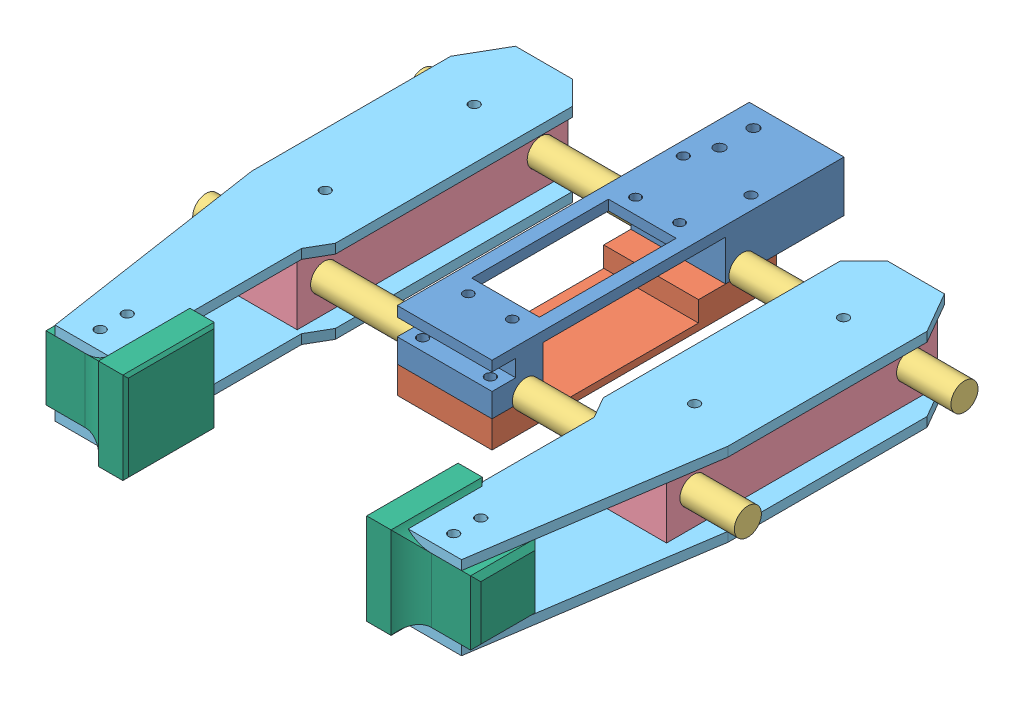
SolidWorks assembly gripper_assembly, configuration Default. Lengths in mm.
Overall size (160 27 162.34).
12 component instances, 6 part files, 24 mates.
Components (placement in the parent):
- gripper_main-1: gripper_main [Default] at (-49.2685 12.2427 53.1978) size (28 15 104)
- top-1: top [Default] at origin size (28 8 84)
- 8mm rod-1: 8mm rod [Default] at (-115.6958 13.7427 -20.8022) x (0 0.664083 0.747659) z (1 0 0) size (8 8 160)
- 8mm rod-2: 8mm rod [Default] at (-115.6958 13.7427 43.1978) x (0 -0.430781 0.902456) z (1 0 0) size (8 8 160)
- cube_part-1: cube_part [Default] at (9.2864 23.2427 51.1978) x (1 0 0) z (0 1 0) size (19 80 19)
- sideplate-1: sideplate [Default] at (14.5778 25.6427 47.7118) x (-1 0 0) z (0 0 1) size (30.8 2.8 139.34)
- sideplate-2: sideplate [Default] at (14.5778 3.8427 47.7118) x (-1 0 0) z (0 0 1) size (30.8 2.8 139.34)
- holdcube-1: holdcube [Default] at (28.2361 23.2427 107.5352) x (-1 0 0) z (0 0 1) size (29 27 27)
- cube_part-2: cube_part [Default] at (-99.8318 4.2427 -28.8022) x (1 0 0) z (0 -1 0) size (19 80 19)
- sideplate-3: sideplate [Default] at (-86.5416 1.8427 47.7118) size (30.8 2.8 139.34)
- sideplate-4: sideplate [Default] at (-86.5416 23.6427 47.7118) size (30.8 2.8 139.34)
- holdcube-2: holdcube [Default] at (-100.1999 4.2427 107.5352) size (29 27 27)
Mates (geometry in assembly coordinates):
- Concentric1: concentric anti-aligned: cylinder of gripper_main-1 through (-21.2685 13.7427 -20.8022) axis (-1 0 0) radius 4; circle of 8mm rod-1
- Coincident2: coincident anti-aligned: cylinder of gripper_main-1 through (-21.2685 13.7427 43.1978) axis (-1 0 0) radius 4; circle of 8mm rod-2
- Concentric2: concentric aligned: circle of 8mm rod-1; circle of cube_part-1
- Concentric3: concentric aligned: circle of 8mm rod-2; circle of cube_part-1
- Coincident6: coincident anti-aligned: plane of cube_part-1 through (9.2864 23.2427 -28.8022) normal (0 1 0); plane of sideplate-1 through (12.9839 23.2427 53.9262) normal (0 -1 0)
- Parallel1: parallel anti-aligned: line of cube_part-1 through (28.2864 4.2427 -28.8022) axis (-1 0 0); line of sideplate-1 through (10.5772 23.2427 -31.8022) axis (1 0 0)
- Coincident13: coincident anti-aligned: plane of cube_part-1 through (9.2864 4.2427 -28.8022) normal (0 -1 0); plane of sideplate-2 through (12.9839 4.2427 53.9262) normal (0 1 0)
- Concentric4: concentric aligned: circle of sideplate-1; circle of sideplate-2
- Parallel3: parallel aligned: line of sideplate-1 through (10.5772 23.2427 -31.8022) axis (1 0 0); line of sideplate-2 through (10.5772 1.4427 -31.8022) axis (1 0 0)
- Coincident17: coincident anti-aligned: plane of sideplate-2 through (12.9839 4.2427 53.9262) normal (0 1 0); plane of holdcube-1 through (28.2361 4.2427 107.5352) normal (0 -1 0)
- Concentric5: concentric aligned: cylinder of sideplate-1 through (16.2361 26.0427 94.0352) axis (0 -1 0) radius 1.5; circle of holdcube-1
- Concentric6: concentric aligned: circle of sideplate-1; circle of holdcube-1
- Coincident21: coincident aligned: plane of 8mm rod-1 through (44.3042 13.7427 -20.8022) normal (1 0 0); plane of 8mm rod-2 through (44.3042 13.7427 43.1978) normal (1 0 0)
- Concentric7: concentric aligned: circle of 8mm rod-1; cylinder of cube_part-2 through (-99.8318 13.7427 -20.8022) axis (1 0 0) radius 4.05
- Concentric8: concentric aligned: circle of 8mm rod-2; circle of cube_part-2
- Coincident22: coincident anti-aligned: plane of cube_part-2 through (-99.8318 23.2427 51.1978) normal (0 1 0); plane of sideplate-4 through (-84.9477 23.2427 53.9262) normal (0 -1 0)
- Coincident23: coincident anti-aligned: plane of cube_part-2 through (-99.8318 4.2427 51.1978) normal (0 -1 0); plane of sideplate-3 through (-84.9477 4.2427 53.9262) normal (0 1 0)
- Concentric9: concentric aligned: circle of sideplate-3; circle of sideplate-4
- Concentric10: concentric aligned: cylinder of sideplate-3 through (-90.541 1.4427 -10.8022) axis (0 1 0) radius 1.5; circle of sideplate-4
- Coincident28: coincident anti-aligned: plane of sideplate-4 through (-84.9477 23.2427 53.9262) normal (0 -1 0); plane of holdcube-2 through (-100.1999 23.2427 107.5352) normal (0 1 0)
- Concentric12: concentric aligned: circle of sideplate-4; circle of holdcube-2
- Concentric13: concentric anti-aligned: circle of sideplate-4; cylinder of holdcube-2 through (-88.1999 23.2427 94.0352) axis (0 -1 0) radius 1.5
- Concentric14: concentric anti-aligned: cylinder of cube_part-2 through (-90.541 23.2427 -10.8022) axis (0 -1 0) radius 1.5; circle of sideplate-3
- Concentric16: concentric anti-aligned: cylinder of cube_part-1 through (18.5772 4.2427 -10.8022) axis (0 1 0) radius 1.5; circle of sideplate-2
